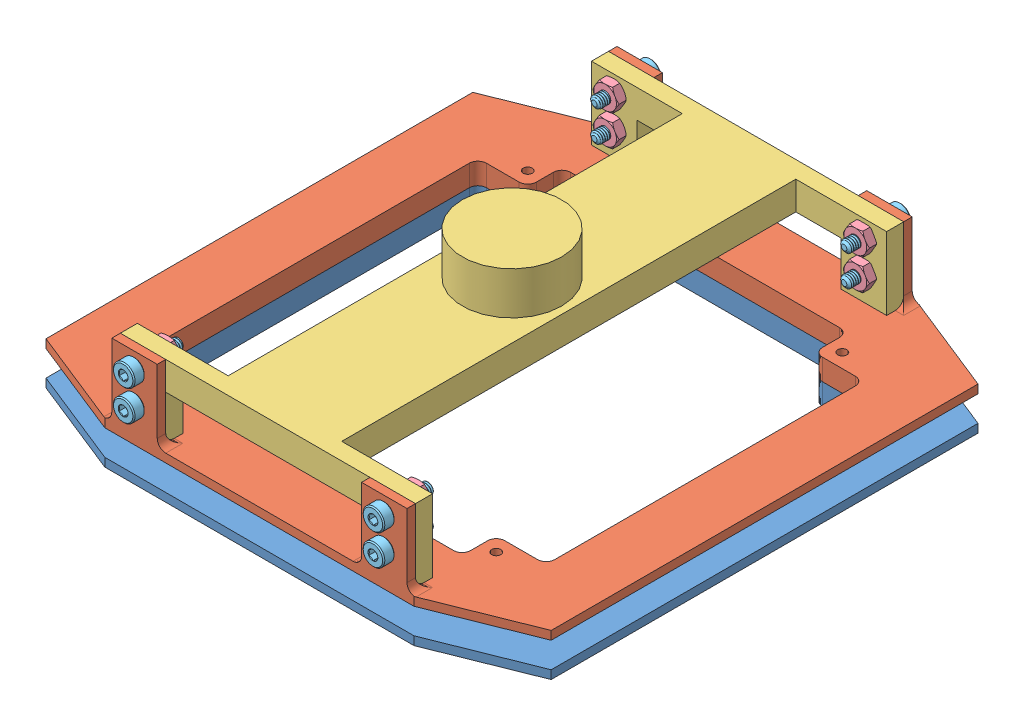
SolidWorks assembly WrappingJigAssembly, configuration Default. Lengths in mm.
Overall size (89 29.89 93.17).
23 component instances, 6 part files, 21 mates.
Components (placement in the parent):
- Zaxis_bottom-1: Zaxis_bottom [Default] at origin size (89 3.75 89)
- Zaxis_top-1: Zaxis_top [Default] at origin size (89 16.55 89)
- jig-1: jig [Default] at (0 14.05 0) x (0 0 -1) z (1 0 0) size (86 20.3 52)
- 91828A111_TYPE 18-8 STAINLESS STEEL HEX NUT-1: 91828A111_TYPE 18-8 STAINLESS STEEL HEX NUT [91828A111] at (-22 13.85 -39.2) x (0.866025 -0.5 0) z (0 0 1) size (4 4.62 1.83)
- 92290A015_TYPE 316 SS SOCKET HEAD CAP SCREW-1: 92290A015_TYPE 316 SS SOCKET HEAD CAP SCREW [92290A015] at (-22 13.85 -36.5) size (3.8 3.8 10.44)
- 92290A015_TYPE 316 SS SOCKET HEAD CAP SCREW-2: 92290A015_TYPE 316 SS SOCKET HEAD CAP SCREW [92290A015] at (-22 8.45 -36.5) size (3.8 3.8 10.44)
- 91828A111_TYPE 18-8 STAINLESS STEEL HEX NUT-2: 91828A111_TYPE 18-8 STAINLESS STEEL HEX NUT [91828A111] at (-22 8.45 -39.2) x (0.866025 -0.5 0) z (0 0 1) size (4 4.62 1.83)
- 91828A111_TYPE 18-8 STAINLESS STEEL HEX NUT-3: 91828A111_TYPE 18-8 STAINLESS STEEL HEX NUT [91828A111] at (22 13.85 -39.2921) x (-0.866025 -0.5 0) z (0 0 -1) size (4 4.62 1.83)
- 92290A015_TYPE 316 SS SOCKET HEAD CAP SCREW-3: 92290A015_TYPE 316 SS SOCKET HEAD CAP SCREW [92290A015] at (22 13.85 -36.5) x (-1 0 0) z (0 0 1) size (3.8 3.8 10.44)
- 92290A015_TYPE 316 SS SOCKET HEAD CAP SCREW-4: 92290A015_TYPE 316 SS SOCKET HEAD CAP SCREW [92290A015] at (22 8.45 -36.5) x (-1 0 0) z (0 0 1) size (3.8 3.8 10.44)
- 91828A111_TYPE 18-8 STAINLESS STEEL HEX NUT-4: 91828A111_TYPE 18-8 STAINLESS STEEL HEX NUT [91828A111] at (22 8.45 -39.2921) x (-0.866025 -0.5 0) z (0 0 -1) size (4 4.62 1.83)
- 91828A111_TYPE 18-8 STAINLESS STEEL HEX NUT-5: 91828A111_TYPE 18-8 STAINLESS STEEL HEX NUT [91828A111] at (-22 13.85 39.2921) x (0.866025 -0.5 0) z (0 0 1) size (4 4.62 1.83)
- 92290A015_TYPE 316 SS SOCKET HEAD CAP SCREW-5: 92290A015_TYPE 316 SS SOCKET HEAD CAP SCREW [92290A015] at (-22 13.85 36.5) x (1 0 0) z (0 0 -1) size (3.8 3.8 10.44)
- 92290A015_TYPE 316 SS SOCKET HEAD CAP SCREW-6: 92290A015_TYPE 316 SS SOCKET HEAD CAP SCREW [92290A015] at (-22 8.45 36.5) x (1 0 0) z (0 0 -1) size (3.8 3.8 10.44)
- 91828A111_TYPE 18-8 STAINLESS STEEL HEX NUT-6: 91828A111_TYPE 18-8 STAINLESS STEEL HEX NUT [91828A111] at (-22 8.45 39.2921) x (0.866025 -0.5 0) z (0 0 1) size (4 4.62 1.83)
- 92290A015_TYPE 316 SS SOCKET HEAD CAP SCREW-7: 92290A015_TYPE 316 SS SOCKET HEAD CAP SCREW [92290A015] at (22 13.85 36.5) x (-1 0 0) z (0 0 -1) size (3.8 3.8 10.44)
- 92290A015_TYPE 316 SS SOCKET HEAD CAP SCREW-8: 92290A015_TYPE 316 SS SOCKET HEAD CAP SCREW [92290A015] at (22 8.45 36.5) x (-1 0 0) z (0 0 -1) size (3.8 3.8 10.44)
- 91828A111_TYPE 18-8 STAINLESS STEEL HEX NUT-7: 91828A111_TYPE 18-8 STAINLESS STEEL HEX NUT [91828A111] at (22 13.85 39.2) x (-0.866025 -0.5 0) z (0 0 -1) size (4 4.62 1.83)
- 91828A111_TYPE 18-8 STAINLESS STEEL HEX NUT-8: 91828A111_TYPE 18-8 STAINLESS STEEL HEX NUT [91828A111] at (22 8.45 39.2) x (-0.866025 -0.5 0) z (0 0 -1) size (4 4.62 1.83)
- 92290A013_TYPE 316 SS SOCKET HEAD CAP SCREW-2: 92290A013_TYPE 316 SS SOCKET HEAD CAP SCREW [92290A013] at (-27.7111 2.25 -30.4845) x (1 0 0) z (0 1 0) size (3.8 3.8 8.44)
- 92290A013_TYPE 316 SS SOCKET HEAD CAP SCREW-3: 92290A013_TYPE 316 SS SOCKET HEAD CAP SCREW [92290A013] at (27.7111 2.25 -30.4845) x (-1 0 0) z (0 1 0) size (3.8 3.8 8.44)
- 92290A013_TYPE 316 SS SOCKET HEAD CAP SCREW-4: 92290A013_TYPE 316 SS SOCKET HEAD CAP SCREW [92290A013] at (-27.7111 2.25 30.4845) x (1 0 0) z (0 1 0) size (3.8 3.8 8.44)
- 92290A013_TYPE 316 SS SOCKET HEAD CAP SCREW-5: 92290A013_TYPE 316 SS SOCKET HEAD CAP SCREW [92290A013] at (27.7111 2.25 30.4845) x (-1 0 0) z (0 1 0) size (3.8 3.8 8.44)
Mates (geometry in assembly coordinates):
- Concentric1: concentric aligned: circle of Zaxis_bottom-1; circle of Zaxis_top-1
- Concentric2: concentric aligned: circle of Zaxis_bottom-1; circle of Zaxis_top-1
- Coincident1: coincident anti-aligned: plane of Zaxis_bottom-1 through (0 0 0) normal (0 1 0); plane of Zaxis_top-1 through (0 0 0) normal (0 -1 0)
- Coincident2: coincident anti-aligned: plane of jig-1 through (0 14.05 0) normal (0 0 -1)
- Coincident3: coincident anti-aligned: plane of Zaxis_top-1 through (0 3.75 0) normal (0 1 0); plane of jig-1 through (-26 3.75 -43) normal (0 -1 0)
- Coincident4: coincident aligned: plane of Zaxis_top-1 through (-26 3.75 -43) normal (-1 0 0); plane of jig-1 through (-26 16.55 -43) normal (-1 0 0)
- Concentric3: concentric anti-aligned: circle of jig-1; circle of 91828A111_TYPE 18-8 STAINLESS STEEL HEX NUT-1
- Coincident6: coincident anti-aligned: plane of Zaxis_top-1 through (27.2332 3.75 -44.5) normal (0 0 -1); plane of 92290A015_TYPE 316 SS SOCKET HEAD CAP SCREW-1 through (-22 13.85 -44.5) normal (0 0 1)
- Concentric4: concentric aligned: circle of Zaxis_top-1; circle of 92290A015_TYPE 316 SS SOCKET HEAD CAP SCREW-1
- Parallel1: parallel aligned: plane of jig-1 through (0 16.55 0) normal (0 1 0); plane of 91828A111_TYPE 18-8 STAINLESS STEEL HEX NUT-1 through (-20.8453 15.85 -38.4) normal (0 1 0)
- Parallel2: parallel aligned: plane of 92290A015_TYPE 316 SS SOCKET HEAD CAP SCREW-1 through (-22 13.85 -36.5) normal (0 1 0)
- Coincident9: coincident anti-aligned: plane of Zaxis_top-1 through (27.2332 3.75 -44.5) normal (0 0 -1); plane of 92290A015_TYPE 316 SS SOCKET HEAD CAP SCREW-2 through (-22 8.45 -44.5) normal (0 0 1)
- Concentric5: concentric anti-aligned: circle of jig-1; circle of 91828A111_TYPE 18-8 STAINLESS STEEL HEX NUT-2
- Coincident10: coincident anti-aligned: plane of jig-1 through (0 14.05 -40) normal (0 0 1); plane of 91828A111_TYPE 18-8 STAINLESS STEEL HEX NUT-2 through (-23.1547 10.45 -40) normal (0 0 -1)
- Parallel3: parallel aligned: plane of jig-1 through (0 16.55 0) normal (0 1 0); plane of 91828A111_TYPE 18-8 STAINLESS STEEL HEX NUT-2 through (-20.8453 10.45 -38.4) normal (0 1 0)
- Concentric6: concentric aligned: circle of Zaxis_top-1; circle of 92290A015_TYPE 316 SS SOCKET HEAD CAP SCREW-2
- Coincident12: coincident anti-aligned: plane of jig-1 through (0 14.05 -40) normal (0 0 1); plane of 91828A111_TYPE 18-8 STAINLESS STEEL HEX NUT-1 through (-23.1547 15.85 -40) normal (0 0 -1)
- Parallel4: parallel aligned: plane of 92290A015_TYPE 316 SS SOCKET HEAD CAP SCREW-2 through (-22 8.45 -36.5) normal (0 1 0)
- Coincident14: coincident anti-aligned: plane of Zaxis_bottom-1 through (0 -3.75 0) normal (0 -1 0); plane of 92290A013_TYPE 316 SS SOCKET HEAD CAP SCREW-2 through (-27.7111 -3.75 -30.4845) normal (0 1 0)
- Concentric7: concentric anti-aligned: circle of Zaxis_bottom-1; circle of 92290A013_TYPE 316 SS SOCKET HEAD CAP SCREW-2
- Parallel5: parallel aligned: plane of 92290A013_TYPE 316 SS SOCKET HEAD CAP SCREW-2 through (-27.7111 2.25 -30.4845) normal (1 0 0)
